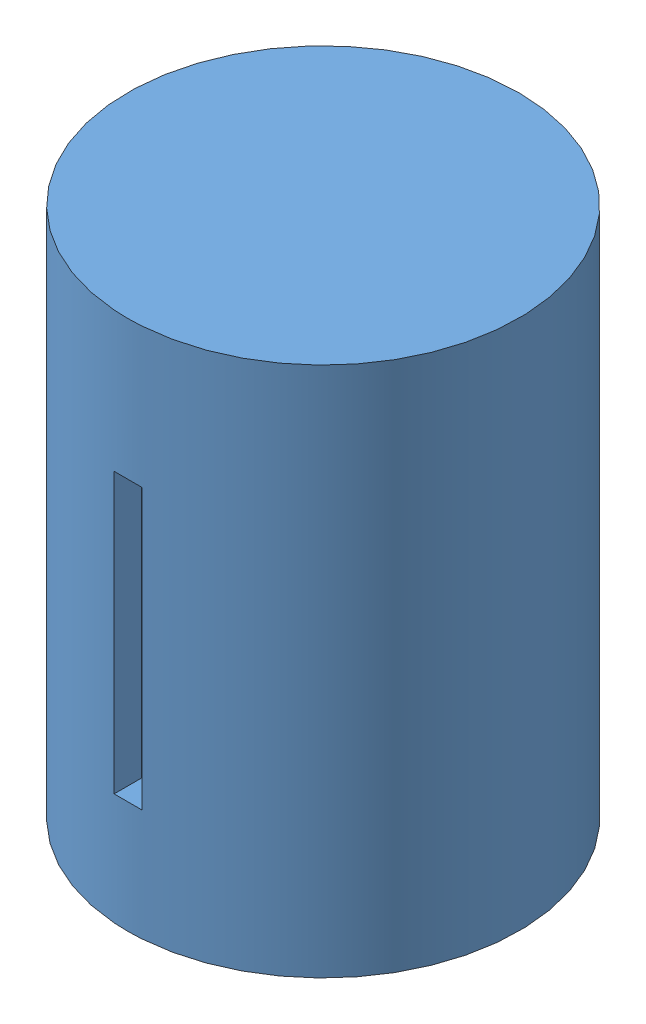
SolidWorks assembly motor w prop, configuration Default. Lengths in mm.
Overall size (28 38 28).
2 component instances, 2 part files, 3 mates.
Components (placement in the parent):
- motor wo prop-1: motor wo prop [Default] at (-15.4297 -14.0096 4.7516) size (28 38 28)
- motor prop-1: motor prop [Default] at (-15.4297 13.9904 4.7516) x (-1 0 0) z (0 0 1) (suppressed, hidden)
Mates (geometry in assembly coordinates):
- Coincident1: coincident anti-aligned: plane of motor wo prop-1 through (-16.4297 13.9904 16.7516) normal (0 0 1); plane of motor prop-1 through (-15.4297 -6.0096 16.7516) normal (0 0 -1)
- Coincident2: coincident aligned: line of motor wo prop-1 through (-14.4297 13.9904 16.7516) axis (-1 0 0); line of motor prop-1 through (-14.4297 13.9904 16.7516) axis (-1 0 0)
- Concentric1: concentric anti-aligned: cylinder of motor wo prop-1 through (-15.4297 23.9904 4.7516) axis (0 -1 0) radius 14; cylinder of motor prop-1 through (-15.4297 -6.0096 4.7516) axis (0 1 0) radius 14
